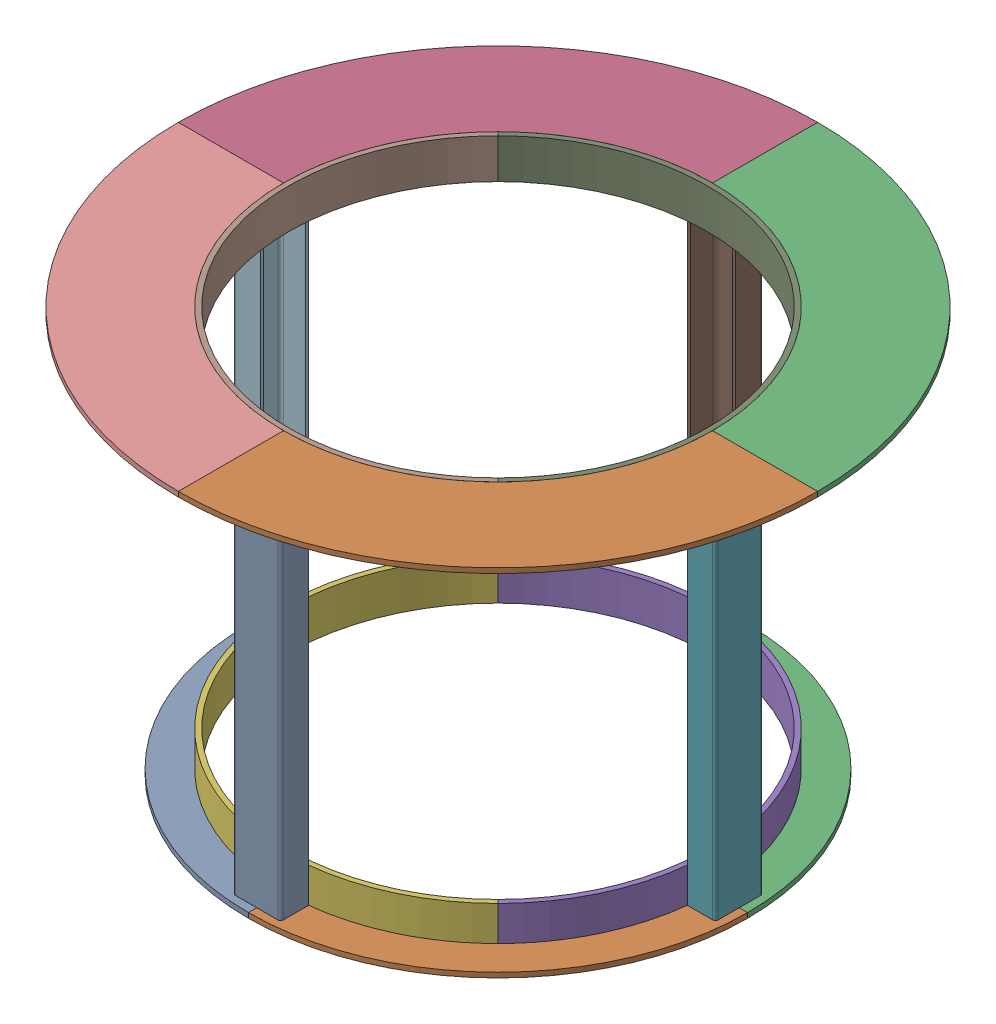
SolidWorks assembly SGB_Assembly, configuration Default. Lengths in mm.
Overall size (1022.22 647.19 1022.22).
16 component instances, 5 part files, 29 mates.
Components (placement in the parent):
- Bottom_Plate-1: Bottom_Plate [Default] at origin size (399.1 7.94 399.1)
- Bottom_Plate-2: Bottom_Plate [Default] x (0 0 -1) z (1 0 0) size (399.1 7.94 399.1)
- Bottom_Plate-3: Bottom_Plate [Default] x (-1 0 0) z (0 0 -1) size (399.1 7.94 399.1)
- Bottom_Plate-4: Bottom_Plate [Default] x (0 0 1) z (-1 0 0) size (399.1 7.94 399.1)
- Bottom_Wall-1: Bottom_Wall [Default] at (0 63.5 0) x (0.707107 0 0.707107) z (0 -1 0) size (685.93 342.96 63.5)
- Bottom_Wall-2: Bottom_Wall [Default] x (0.707107 0 0.707107) z (0 1 0) size (685.93 342.96 63.5)
- Risers-1: Risers [Default] at (363.5207 7.9375 0) x (0 0 1) z (-1 0 0) size (76.2 631.32 44.45)
- Top_Wall-1: Top_Wall [Default] at (0 647.192 0) x (-0.707107 0 -0.707107) z (0 -1 0) size (685.93 342.96 63.5)
- Top_Wall-2: Top_Wall [Default] at (0 583.692 0) x (-0.707107 0 -0.707107) z (0 1 0) size (685.93 342.96 63.5)
- Top_Plate-1: Top_Plate [Default] at (0 639.2545 0) size (511.11 7.94 511.11)
- Risers-2: Risers [Default] at (0 7.9375 -363.5207) size (76.2 631.32 44.45)
- Risers-3: Risers [Default] at (-363.5207 7.9375 0) x (0 0 -1) z (1 0 0) size (76.2 631.32 44.45)
- Risers-4: Risers [Default] at (0 7.9375 363.5207) x (-1 0 0) z (0 0 -1) size (76.2 631.32 44.45)
- Top_Plate-2: Top_Plate [Default] at (0 639.2545 0) x (0 0 -1) z (1 0 0) size (511.11 7.94 511.11)
- Top_Plate-3: Top_Plate [Default] at (0 639.2545 0) x (-1 0 0) z (0 0 -1) size (511.11 7.94 511.11)
- Top_Plate-4: Top_Plate [Default] at (0 639.2545 0) x (0 0 1) z (-1 0 0) size (511.11 7.94 511.11)
Mates (geometry in assembly coordinates):
- Coincident1: coincident anti-aligned: plane of Bottom_Plate-1 through (0 7.9375 0) normal (1 0 0); plane of Bottom_Plate-2 through (0 7.9375 0) normal (-1 0 0)
- Coincident2: coincident aligned: plane of Bottom_Plate-1 through (0 7.9375 0) normal (0 1 0); plane of Bottom_Plate-2 through (0 7.9375 0) normal (0 1 0)
- Coincident3: coincident aligned: line of Bottom_Plate-1 through (0 7.9375 399.0975) axis (0 -1 0); line of Bottom_Plate-2 through (0 7.9375 399.0975) axis (0 -1 0)
- Coincident4: coincident anti-aligned: plane of Bottom_Plate-2 through (0 7.9375 0) normal (0 0 -1); plane of Bottom_Plate-3 through (0 7.9375 0) normal (0 0 1)
- Coincident5: coincident aligned: plane of Bottom_Plate-2 through (0 7.9375 0) normal (0 1 0); plane of Bottom_Plate-3 through (0 7.9375 0) normal (0 1 0)
- Coincident6: coincident aligned: line of Bottom_Plate-2 through (342.9635 7.9375 0) axis (0 -1 0); line of Bottom_Plate-3 through (342.9635 7.9375 0) axis (0 -1 0)
- Coincident7: coincident anti-aligned: plane of Bottom_Plate-3 through (0 7.9375 0) normal (-1 0 0); plane of Bottom_Plate-4 through (0 7.9375 0) normal (1 0 0)
- Coincident8: coincident aligned: plane of Bottom_Plate-3 through (0 7.9375 0) normal (0 1 0); plane of Bottom_Plate-4 through (0 7.9375 0) normal (0 1 0)
- Coincident9: coincident aligned: line of Bottom_Plate-3 through (0 7.9375 -399.0975) axis (0 -1 0); line of Bottom_Plate-4 through (0 7.9375 -399.0975) axis (0 -1 0)
- Concentric1: concentric anti-aligned: cylinder of Bottom_Plate-3 through (0 7.9375 0) axis (0 -1 0) radius 342.9635; cylinder of Bottom_Wall-1 through (0 0 0) axis (0 1 0) radius 342.9635
- Coincident10: coincident aligned: plane of Bottom_Plate-4 through (0 0 0) normal (0 -1 0); plane of Bottom_Wall-1 through (0 0 0) normal (0 -1 0)
- Coincident11: coincident aligned: plane of Bottom_Wall-1 through (-242.5118 0 -242.5118) normal (-0.707107 0 0.707107)
- Coincident12: coincident anti-aligned: plane of Bottom_Wall-1 through (-242.5118 0 -242.5118) normal (-0.707107 0 0.707107); plane of Bottom_Wall-2 through (-242.5118 63.5 -242.5118) normal (0.707107 0 -0.707107)
- Coincident13: coincident aligned: plane of Bottom_Plate-4 through (0 0 0) normal (0 -1 0); plane of Bottom_Wall-2 through (0 0 0) normal (0 -1 0)
- Concentric2: concentric aligned: cylinder of Bottom_Plate-4 through (0 7.9375 0) axis (0 -1 0) radius 342.9635; cylinder of Bottom_Wall-2 through (0 63.5 0) axis (0 -1 0) radius 342.9635
- Coincident14: coincident anti-aligned: plane of Bottom_Plate-2 through (0 7.9375 0) normal (0 1 0); plane of Risers-1 through (381.4277 7.9375 33.782) normal (0 -1 0)
- Tangent3: tangent: cylinder of Bottom_Wall-1 through (0 0 0) axis (0 1 0) radius 342.9635; line of Risers-1 through (341.2957 639.2545 -33.782) axis (0 -1 0)
- Tangent4: tangent: cylinder of Bottom_Wall-2 through (0 63.5 0) axis (0 -1 0) radius 342.9635; line of Risers-1 through (341.2957 639.2545 33.782) axis (0 -1 0)
- Symmetric1: symmetric aligned: plane of Risers-1 through (381.4277 639.2545 -38.1) normal (0 0 -1); plane of Risers-1 through (381.4277 639.2545 38.1) normal (0 0 1)
- Coincident17: coincident anti-aligned: plane of Top_Wall-1 through (-236.8992 583.692 -236.8992) normal (0.707107 0 -0.707107); plane of Top_Wall-2 through (-236.8992 647.192 -236.8992) normal (-0.707107 0 0.707107)
- Coincident18: coincident aligned: plane of Top_Wall-1 through (0 583.692 0) normal (0 -1 0); plane of Top_Wall-2 through (0 583.692 0) normal (0 -1 0)
- Coincident19: coincident anti-aligned: line of Top_Wall-1 through (242.5118 583.692 242.5118) axis (0 1 0); line of Top_Wall-2 through (242.5118 647.192 242.5118) axis (0 -1 0)
- Tangent5: tangent: line of Risers-1 through (341.2957 639.2545 -33.782) axis (0 -1 0); cylinder of Top_Wall-2 through (0 647.192 0) axis (0 -1 0) radius 342.9635
- Distance1: distance = 7.9375 mm aligned: plane of Top_Wall-1 through (0 647.192 0) normal (0 1 0); plane of Risers-1 through (381.4277 639.2545 33.782) normal (0 1 0)
- Coincident22: coincident: line of Risers-1 through (341.2957 639.2545 33.782) axis (0 -1 0); cylinder of Top_Wall-2 through (0 647.192 0) axis (0 -1 0) radius 342.9635
- Coincident23: coincident: line of Top_Wall-1 through (-242.5118 583.692 -242.5118) axis (0 1 0)
- Concentric3: concentric anti-aligned: cylinder of Top_Wall-1 through (0 583.692 0) axis (0 1 0) radius 342.9635; cylinder of Top_Plate-1 through (0 647.192 0) axis (0 -1 0) radius 342.9635
- Coincident24: coincident anti-aligned: plane of Risers-3 through (-381.4277 639.2545 -33.782) normal (0 1 0); plane of Top_Plate-1 through (0 639.2545 0) normal (0 -1 0)
- Coincident25: coincident anti-aligned: plane of Top_Plate-1 through (0 647.192 0) normal (0 0 -1)
